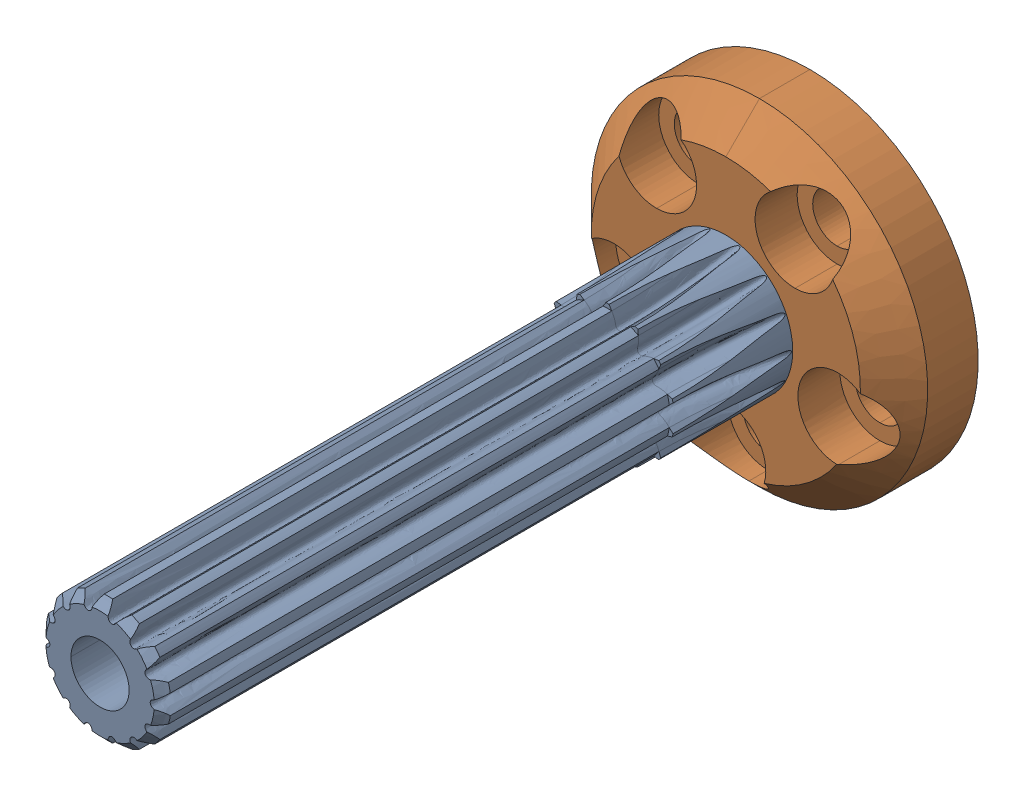
SolidWorks assembly 217-6515-200 Rev5.STEP, configuration Default. Lengths in mm.
Overall size (20 20 42.21).
2 component instances, 2 part files, 0 mates.
Components (placement in the parent):
- 217-6515-201 Rev6.STEP-1: 217-6515-201 Rev6.STEP [Default] at (0 0 21.1) size (9.31 9.33 42.21)
- 217-6515-202 Rev6.STEP-1: 217-6515-202 Rev6.STEP [Default] x (-1 0 0) z (0 1 0) size (20 5.01 20)
